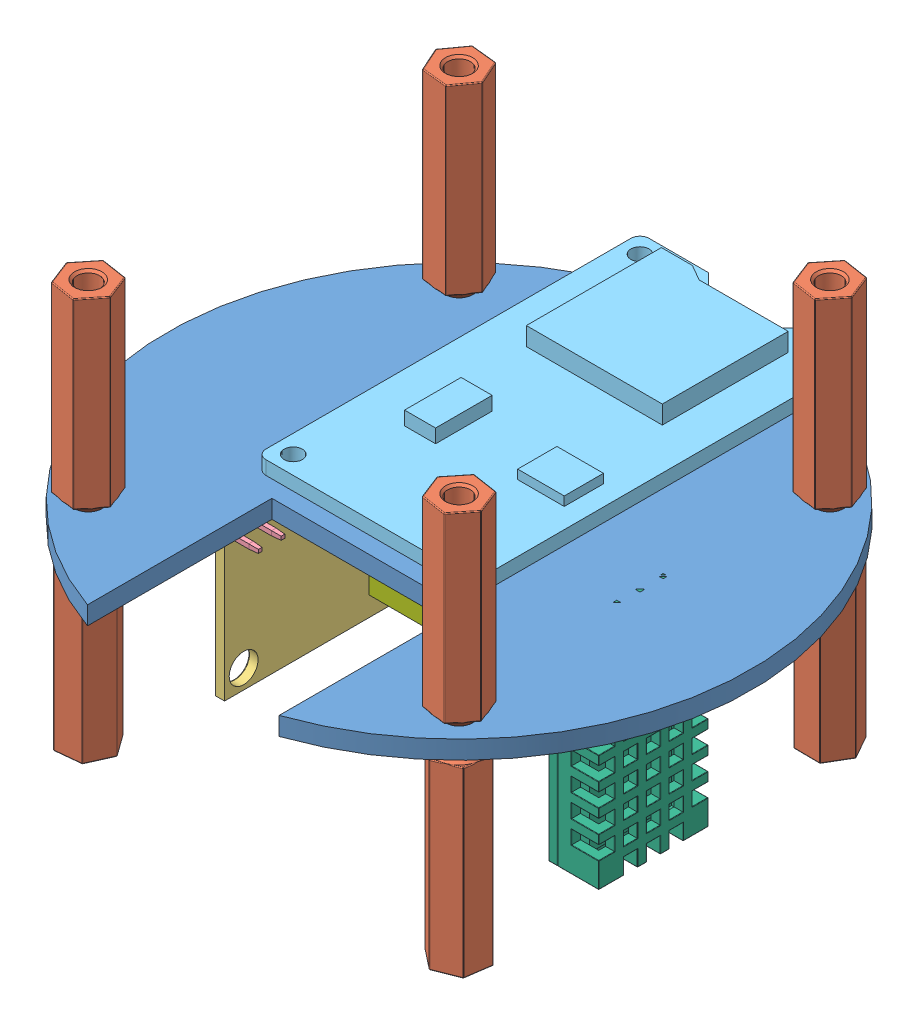
SolidWorks assembly Ensam_pcb_sensores, configuration Predeterminado. Lengths in mm.
Overall size (70.17 44.5 62.56).
22 component instances, 7 part files, 20 mates.
Components (placement in the parent):
- power_pcb-2: power_pcb [Predeterminado] at origin size (64 2 62.23)
- separador_bronce_28mm-3: separador_bronce_28mm [Predeterminado] at (-20.5243 3 20.5401) x (0.36247 0 0.931995) z (0 -1 0) size (5.74 5 28)
- separador_bronce_28mm-4: separador_bronce_28mm [Predeterminado] at (20.1173 3 20.5401) x (0.363768 0 0.93149) z (0 -1 0) size (5.74 5 28)
- separador_bronce_28mm-5: separador_bronce_28mm [Predeterminado] at (-20.5243 3 -20.1015) x (-0.408173 0 -0.912905) z (0 -1 0) size (5.74 5 28)
- separador_bronce_28mm-6: separador_bronce_28mm [Predeterminado] at (20.1173 3 -20.1015) x (0.36247 0 0.931995) z (0 -1 0) size (5.74 5 28)
- separador_bronce_28mm-7: separador_bronce_28mm [Predeterminado] at (-20.5243 -1 -20.1015) x (-0.292052 0 -0.956402) z (0 1 0) size (5.74 5 28)
- separador_bronce_28mm-8: separador_bronce_28mm [Predeterminado] at (20.1173 -1 -20.1015) x (-0.491421 0 -0.870922) z (0 1 0) size (5.74 5 28)
- separador_bronce_28mm-9: separador_bronce_28mm [Predeterminado] at (20.1173 -1 20.5401) x (-0.786007 0 -0.618217) z (0 1 0) size (5.74 5 28)
- separador_bronce_28mm-10: separador_bronce_28mm [Predeterminado] at (-20.5243 -1 20.5401) x (-0.585988 0 -0.81032) z (0 1 0) size (5.74 5 28)
- GY521-1: GY521 [Predeterminado] at (-16.8221 -12.1995 -0.6196) x (0 0 -1) z (0 1 0) size (20.52 65.96 22.5)
  - Placa_GY521-1: Placa_GY521 [Predeterminado] at (0.1306 -0.272 0) size (20.27 65.96 16.25)
  - PIN_90deg-1: PIN_90deg [Predeterminado] at (-9.1926 0.728 6.9495) x (-1 0 0) z (0 0 -1) size (2.5 7.15 8.5)
  - PIN_90deg-2: PIN_90deg [Predeterminado] at (-6.6926 0.728 6.9495) x (-1 0 0) z (0 0 -1) size (2.5 7.15 8.5)
  - PIN_90deg-3: PIN_90deg [Predeterminado] at (-4.1926 0.728 6.9495) x (-1 0 0) z (0 0 -1) size (2.5 7.15 8.5)
  - PIN_90deg-4: PIN_90deg [Predeterminado] at (-1.6926 0.728 6.9495) x (-1 0 0) z (0 0 -1) size (2.5 7.15 8.5)
  - PIN_90deg-5: PIN_90deg [Predeterminado] at (0.8074 0.728 6.9495) x (-1 0 0) z (0 0 -1) size (2.5 7.15 8.5)
  - PIN_90deg-6: PIN_90deg [Predeterminado] at (3.3074 0.728 6.9495) x (-1 0 0) z (0 0 -1) size (2.5 7.15 8.5)
  - PIN_90deg-7: PIN_90deg [Predeterminado] at (5.8074 0.728 6.9495) x (-1 0 0) z (0 0 -1) size (2.5 7.15 8.5)
  - PIN_90deg-8: PIN_90deg [Predeterminado] at (8.3074 0.728 6.9495) x (-1 0 0) z (0 0 -1) size (2.5 7.15 8.5)
- micro SD-1: micro SD [Predeterminado] at (-0.7076 3.5 -11.1079) x (0 0 -1) z (1 0 0) size (42 5 24)
- DHT11-1: DHT11 [Default] at (15.3698 -6 -6.0125) x (0 0 1) z (1 0 0) size (12 23.5 5.5)
- BMP180_SHIELD_13x10.5-1: BMP180_SHIELD_13x10.5 [Predeterminado] at (0.1163 -2.5 -0.7271) x (0 0 -1) z (0 -1 0) size (13 10.5 4.25)
Mates (geometry in assembly coordinates):
- Concéntrica8: concentric anti-aligned: cylinder of power_pcb-2 through (-20.5243 2 20.5401) axis (0 -1 0) radius 1.5; cylinder of separador_bronce_28mm-3 through (-20.5243 -5 20.5401) axis (0 1 0) radius 1.5
- Concéntrica9: concentric anti-aligned: cylinder of power_pcb-2 through (20.1173 2 20.5401) axis (0 -1 0) radius 1.5; cylinder of separador_bronce_28mm-4 through (20.1173 -5 20.5401) axis (0 1 0) radius 1.5
- Concéntrica10: concentric anti-aligned: cylinder of power_pcb-2 through (-20.5243 2 -20.1015) axis (0 -1 0) radius 1.5; cylinder of separador_bronce_28mm-5 through (-20.5243 -5 -20.1015) axis (0 1 0) radius 1.5
- Concéntrica11: concentric anti-aligned: cylinder of power_pcb-2 through (20.1173 2 -20.1015) axis (0 -1 0) radius 1.5; cylinder of separador_bronce_28mm-6 through (20.1173 -5 -20.1015) axis (0 1 0) radius 1.5
- Concéntrica12: concentric anti-aligned: cylinder of separador_bronce_28mm-5 through (-20.5243 -5 -20.1015) axis (0 1 0) radius 1.5; cylinder of separador_bronce_28mm-7 through (-20.5243 7 -20.1015) axis (0 -1 0) radius 1.5
- Concéntrica13: concentric anti-aligned: cylinder of separador_bronce_28mm-6 through (20.1173 -5 -20.1015) axis (0 1 0) radius 1.5; cylinder of separador_bronce_28mm-8 through (20.1173 7 -20.1015) axis (0 -1 0) radius 1.5
- Concéntrica14: concentric anti-aligned: cylinder of separador_bronce_28mm-4 through (20.1173 -5 20.5401) axis (0 1 0) radius 1.5; cylinder of separador_bronce_28mm-9 through (20.1173 7 20.5401) axis (0 -1 0) radius 1.5
- Concéntrica15: concentric anti-aligned: cylinder of separador_bronce_28mm-3 through (-20.5243 -5 20.5401) axis (0 1 0) radius 1.5; cylinder of separador_bronce_28mm-10 through (-20.5243 7 20.5401) axis (0 -1 0) radius 1.5
- Coincidente12: coincident aligned: circle of power_pcb-2; circle of separador_bronce_28mm-10
- Coincidente13: coincident anti-aligned: circle of power_pcb-2; circle of separador_bronce_28mm-3
- Coincidente14: coincident anti-aligned: circle of power_pcb-2; circle of separador_bronce_28mm-7
- Coincidente15: coincident aligned: circle of power_pcb-2; circle of separador_bronce_28mm-5
- Coincidente16: coincident aligned: circle of power_pcb-2; circle of separador_bronce_28mm-4
- Coincidente17: coincident anti-aligned: circle of power_pcb-2; circle of separador_bronce_28mm-9
- Coincidente18: coincident aligned: circle of power_pcb-2; circle of separador_bronce_28mm-8
- Coincidente20: coincident anti-aligned: circle of power_pcb-2; circle of separador_bronce_28mm-6
- Coincidente24: coincident anti-aligned: plane of power_pcb-2 through (-0.2035 2 0.2193) normal (0 1 0); plane of micro SD-1 through (-0.7076 2 -11.1079) normal (0 -1 0)
- Coincidente25: coincident aligned: plane of power_pcb-2 through (-0.2035 2 0.2193) normal (0 1 0); plane of GY521-1/PIN_90deg-1 through (-20.5501 2 8.573) normal (0 1 0)
- Coincidente26: coincident aligned: plane of power_pcb-2 through (-0.2035 2 0.2193) normal (0 1 0); plane of DHT11-1 through (15.3698 2 -6.0125) normal (0 1 0)
- Distancia2: distance = 2.5 mm aligned: plane of BMP180_SHIELD_13x10.5-1 through (0.1163 -2.5 -0.7271) normal (0 -1 0); plane of power_pcb-2 through (-0.2035 0 0.2193) normal (0 -1 0)
